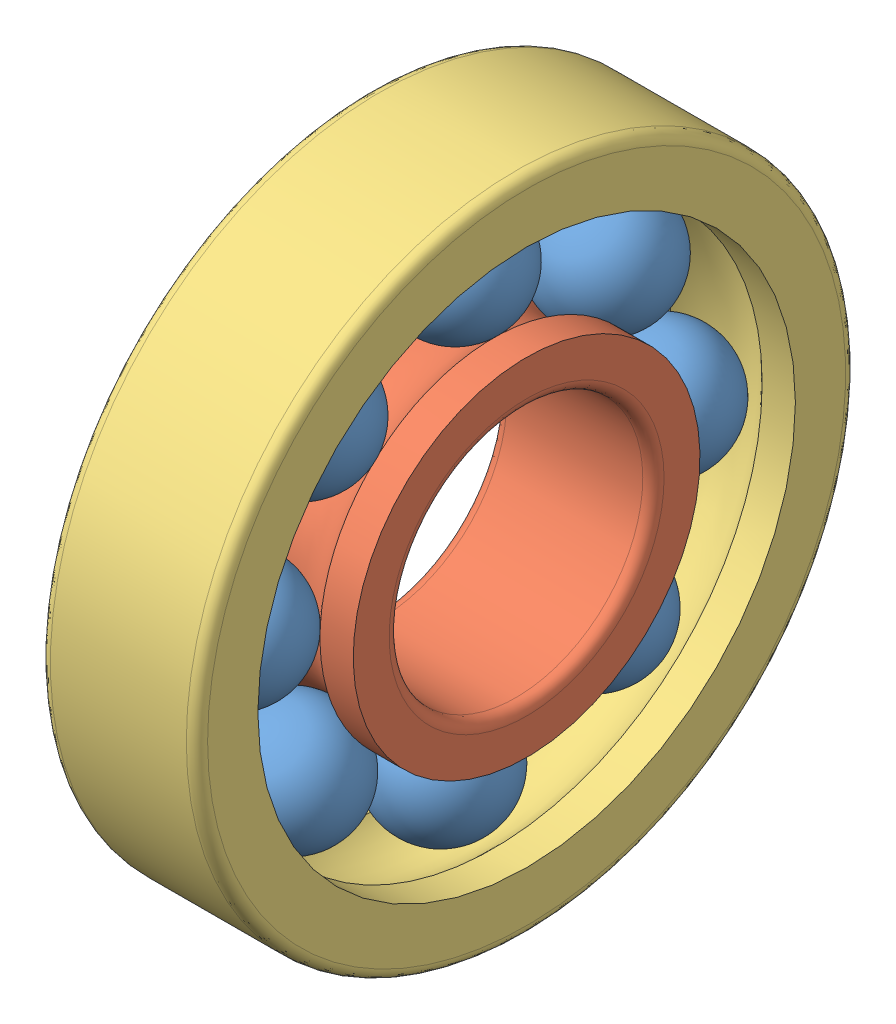
SolidWorks assembly Assem1, configuration Default. Lengths in mm.
Overall size (37.85 130 130).
10 component instances, 3 part files, 3 mates.
Components (placement in the parent):
- ball-1: ball [Default] at (59.8745 -13.4958 -76.219) x (0.810176 -0.113683 -0.575058) z (0.226167 -0.844433 0.485573) size (24 24 24)
- inner ring-1: inner ring [Default] at (59.798 -55.6464 -74.7457) x (1 0 0) z (0 0.977494 -0.210963) size (31 68.37 68.37)
- outer ring-1: outer ring [Default] at (59.6377 -55.6464 -74.7457) size (31 130 130)
- ball-2: ball [Default] at (59.8745 -26.8832 -105.5924) x (0.810176 -0.487013 -0.326241) z (0.226167 -0.253752 0.940456) size (24 24 24)
- ball-3: ball [Default] at (59.8745 -57.1196 -116.8962) x (0.810176 -0.575058 0.113683) z (0.226167 0.485573 0.844433) size (24 24 24)
- ball-4: ball [Default] at (59.8745 -86.4931 -103.5088) x (0.810176 -0.326241 0.487013) z (0.226167 0.940456 0.253752) size (24 24 24)
- ball-5: ball [Default] at (59.8745 -97.7969 -73.2724) x (0.810176 0.113683 0.575058) z (0.226167 0.844433 -0.485573) size (24 24 24)
- ball-6: ball [Default] at (59.8745 -84.4095 -43.8989) x (0.810176 0.487013 0.326241) z (0.226167 0.253752 -0.940456) size (24 24 24)
- ball-7: ball [Default] at (59.8745 -54.1731 -32.5951) x (0.810176 0.575058 -0.113683) z (0.226167 -0.485573 -0.844433) size (24 24 24)
- ball-8: ball [Default] at (59.8745 -24.7996 -45.9825) x (0.810176 0.326241 -0.487013) z (0.226167 -0.940456 -0.253752) size (24 24 24)
Mates (geometry in assembly coordinates):
- Width1: width aligned: plane of outer ring-1 through (44.298 -2.6464 -74.7457) normal (-1 0 0); plane of outer ring-1 through (75.298 -2.6464 -74.7457) normal (1 0 0); plane of inner ring-1 through (44.298 -62.8582 -108.1615) normal (-1 0 0); plane of inner ring-1 through (75.298 -62.8582 -108.1615) normal (1 0 0)
- Coincident7: coincident aligned: axis of inner ring-1 through (88.5338 -55.6464 -74.7457) axis (-1 0 0); axis of outer ring-1 through (75.298 -55.6464 -74.7457) axis (-1 0 0)
- Tangent25: tangent: torus of inner ring-1; sphere of ball-7
